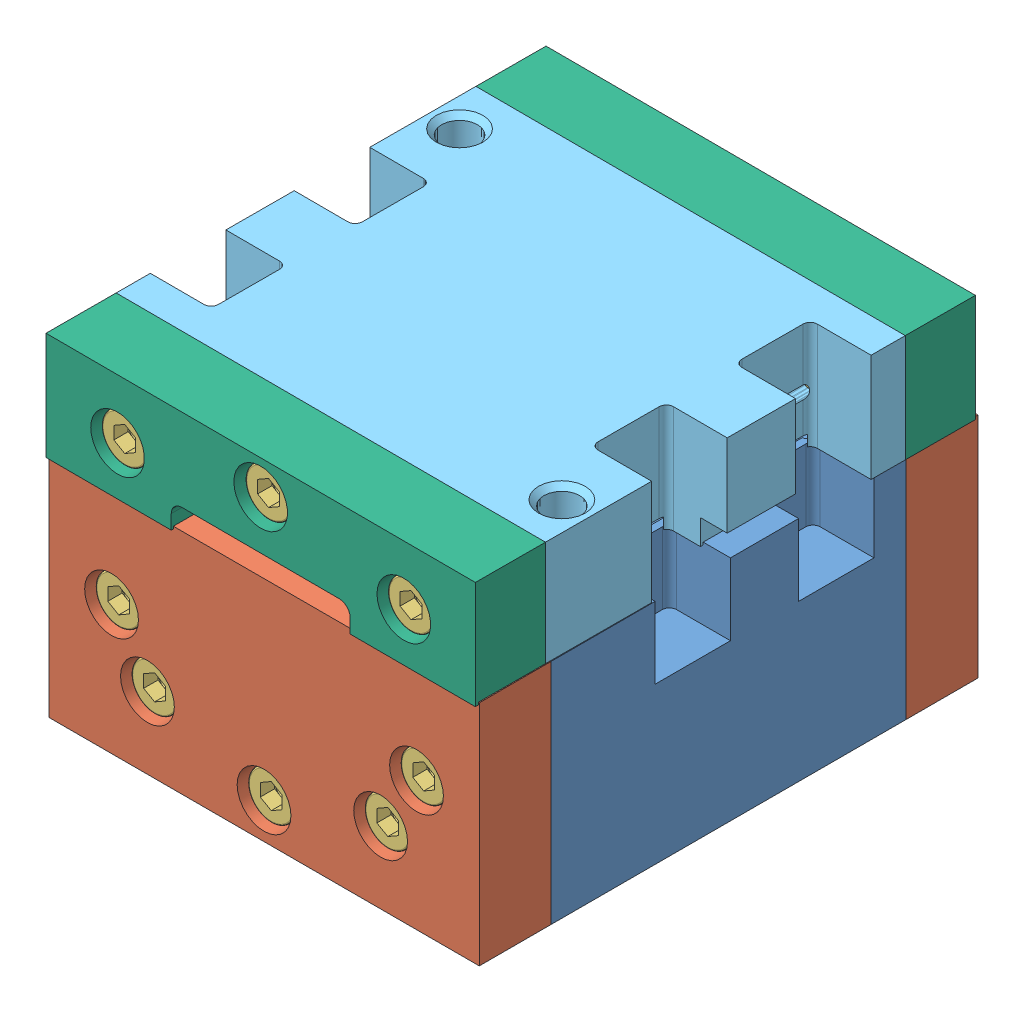
SolidWorks assembly Сборка2, configuration Default. Lengths in mm.
Overall size (120.38 92.82 139.81).
30 component instances, 7 part files, 1 mates.
Components (placement in the parent):
- Сборка1-1: Сборка1 [По умолчанию] at (46.1455 48.573 101.7886) size (120 88.5 139)
  - Матрица-1: Матрица [Default] at origin size (120 63.5 99)
  - Боковина Пресс-формы.-1: Боковина Пресс-формы. [По умолчанию] at (0 36.1757 49.5) size (120 63.5 20)
  - Боковина Пресс-формы.-3: Боковина Пресс-формы. [По умолчанию] at (0 36.1757 -49.5) x (-1 0 0) z (0 0 -1) size (120 63.5 20)
  - socket head cap screw_iso-1: socket head cap screw_iso [ISO 4762 M8 x 16 - 16N] at (-42.5 36 -67.5) x (0 0 1) z (-1 0 0) size (24 13 13)
  - socket head cap screw_iso-2: socket head cap screw_iso [ISO 4762 M8 x 16 - 16N] at (-32.5 20 -67.5) x (0 0 1) z (-1 0 0) size (24 13 13)
  - socket head cap screw_iso-3: socket head cap screw_iso [ISO 4762 M8 x 16 - 16N] at (0 10 -67.5) x (0 0 1) z (-1 0 0) size (24 13 13)
  - socket head cap screw_iso-4: socket head cap screw_iso [ISO 4762 M8 x 16 - 16N] at (32.5 20 -67.5) x (0 0 1) z (-1 0 0) size (24 13 13)
  - socket head cap screw_iso-5: socket head cap screw_iso [ISO 4762 M8 x 16 - 16N] at (42.5 36 -67.5) x (0 0 1) z (-1 0 0) size (24 13 13)
  - socket head cap screw_iso-6: socket head cap screw_iso [ISO 4762 M8 x 16 - 16N] at (42.5 36 67.5) x (0 0 -1) z (1 0 0) size (24 13 13)
  - socket head cap screw_iso-7: socket head cap screw_iso [ISO 4762 M8 x 16 - 16N] at (32.5 20 67.5) x (0 0 -1) z (1 0 0) size (24 13 13)
  - socket head cap screw_iso-10: socket head cap screw_iso [ISO 4762 M8 x 16 - 16N] at (-42.5 36 67.5) x (0 0 -1) z (1 0 0) size (24 13 13)
  - socket head cap screw_iso-8: socket head cap screw_iso [ISO 4762 M8 x 16 - 16N] at (0 10 67.5) x (0 0 -1) z (1 0 0) size (24 13 13)
  - socket head cap screw_iso-9: socket head cap screw_iso [ISO 4762 M8 x 16 - 16N] at (-32.5 20 67.5) x (0 0 -1) z (1 0 0) size (24 13 13)
  - socket head cap screw_iso-11: socket head cap screw_iso [ISO 4762 M8 x 16 - 16N] at (-32.5 20 67.5) x (0 0 -1) z (1 0 0) size (24 13 13)
  - socket head cap screw_iso-12: socket head cap screw_iso [ISO 4762 M8 x 16 - 16N] at (-42.5 36 67.5) x (0 0 -1) z (1 0 0) size (24 13 13)
  - Направляющая-1: Направляющая [Default] at (51.9816 33.5 38) x (0 1 0) z (-0.458497 0 -0.888696) size (55 10 10) (hidden)
  - Направляющая-3: Направляющая [Default] at (-52 33.5 -37) x (0 1 0) z (-0.61776 0 -0.786366) size (55 10 10) (hidden)
  - Подставка-2: Подставка [По умолчанию] at (0 48 -27) x (0.955678 0 -0.294415) z (0 -1 0) size (12 12 36)
  - Подставка-3: Подставка [По умолчанию] at (0 48 27) x (0.972927 0 -0.231111) z (0 -1 0) size (12 12 36)
- Сборка3-1: Сборка3 [По умолчанию] at (-38.0774 -38.1137 -141.3789) x (0.999996 0 0.002734) z (-0.002734 0 0.999996) size (120 30 139)
  - Пуансон-2: Пуансон [Default] at (84.7865 149.5092 243.5787) size (120 30 100)
  - Боковина пуансона-3: Боковина пуансона [Default] at (84.7865 164.5092 193.5787) x (1 0 0) z (0 0 -1) size (120 30 19.5)
  - Боковина пуансона-4: Боковина пуансона [Default] at (84.7865 164.5092 293.5787) x (-1 0 0) z (0 0 1) size (120 30 19.5)
  - socket head cap screw_iso-1: socket head cap screw_iso [ISO 4762 M8 x 16 - 16N] at (44.7865 163.0092 311.0787) x (0 0 -1) z (1 0 0) size (24 13 13)
  - socket head cap screw_iso-2: socket head cap screw_iso [ISO 4762 M8 x 16 - 16N] at (124.7865 163.0092 311.0787) x (0 0 -1) z (1 0 0) size (24 13 13)
  - socket head cap screw_iso-3: socket head cap screw_iso [ISO 4762 M8 x 16 - 16N] at (85.1489 170.29 311.2498) x (0 0 -1) z (1 0 0) size (24 13 13)
  - socket head cap screw_iso-4: socket head cap screw_iso [ISO 4762 M8 x 16 - 16N] at (124.7865 163.0092 176.0787) x (0 0 1) z (-1 0 0) size (24 13 13)
  - socket head cap screw_iso-5: socket head cap screw_iso [ISO 4762 M8 x 16 - 16N] at (84.7865 170.0092 176.0787) x (0 0 1) z (-1 0 0) size (24 13 13)
  - socket head cap screw_iso-6: socket head cap screw_iso [ISO 4762 M8 x 16 - 16N] at (44.7865 163.0092 176.0787) x (0 0 1) z (-1 0 0) size (24 13 13)
Mates (geometry in assembly coordinates):
- Концентричный20: concentric anti-aligned: cylinder of Сборка1-1/Матрица-1 through (-5.8545 82.073 64.7886) axis (0 1 0) radius 5; cylinder of Сборка3-1/Пуансон-2 through (-5.8545 163.3955 64.7886) axis (0 -1 0) radius 5
